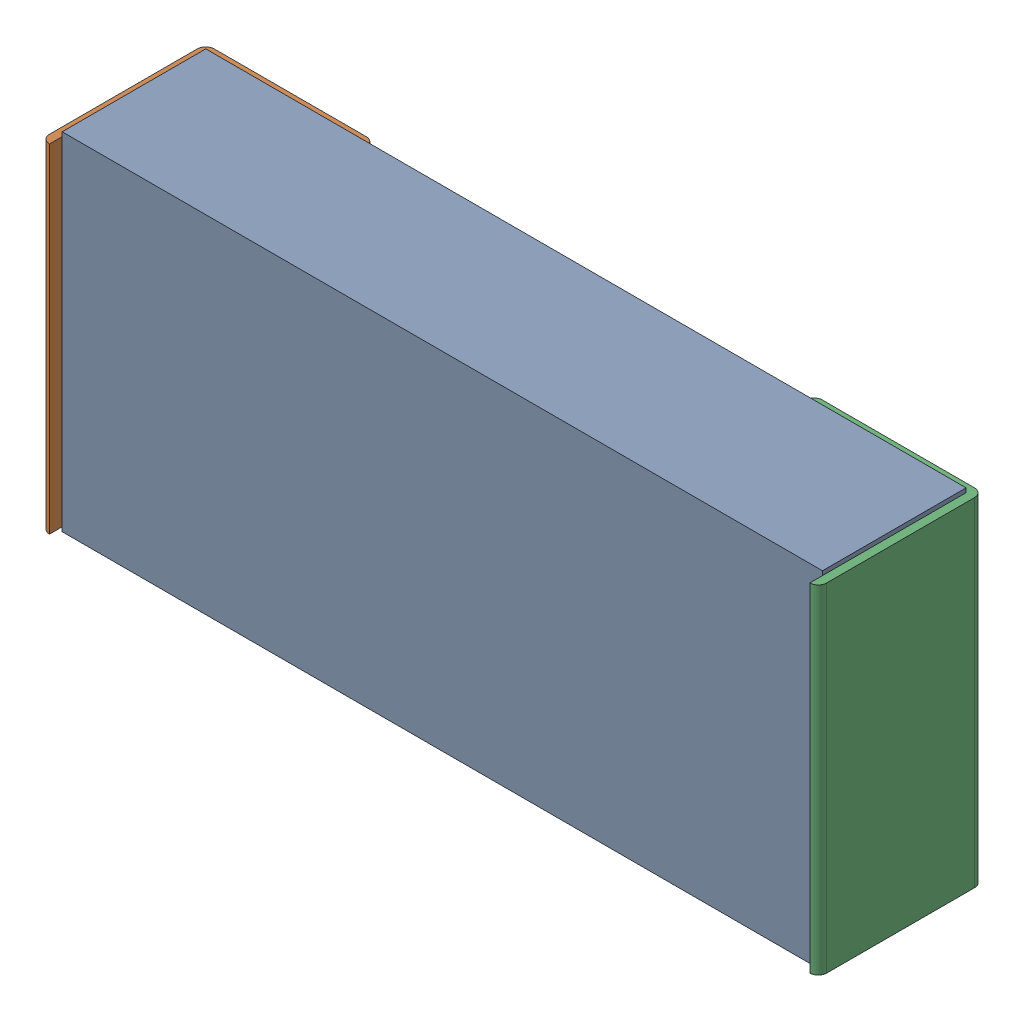
SolidWorks assembly R2, configuration Predeterminado. Lengths in mm.
Overall size (2.34 1.04 0.5).
4 component instances, 3 part files, 0 mates.
Components (placement in the parent):
- Open CASCADE STEP translator 6.8 1.13.1-1: Open CASCADE STEP translator 6.8 1.13.1 [Predeterminado] at origin size (2.34 1.04 0.5)
  - Body_1_5-1: Body_1_5 [Predeterminado] at origin size (2.29 1.04 0.43)
  - Pin_1_4-1: Pin_1_4 [Predeterminado] at (0.3048 0 0) x (-1 0 0) z (0 0 1) size (0.51 1.02 0.5)
  - Pin_2_4-1: Pin_2_4 [Predeterminado] at origin size (0.51 1.02 0.5)
